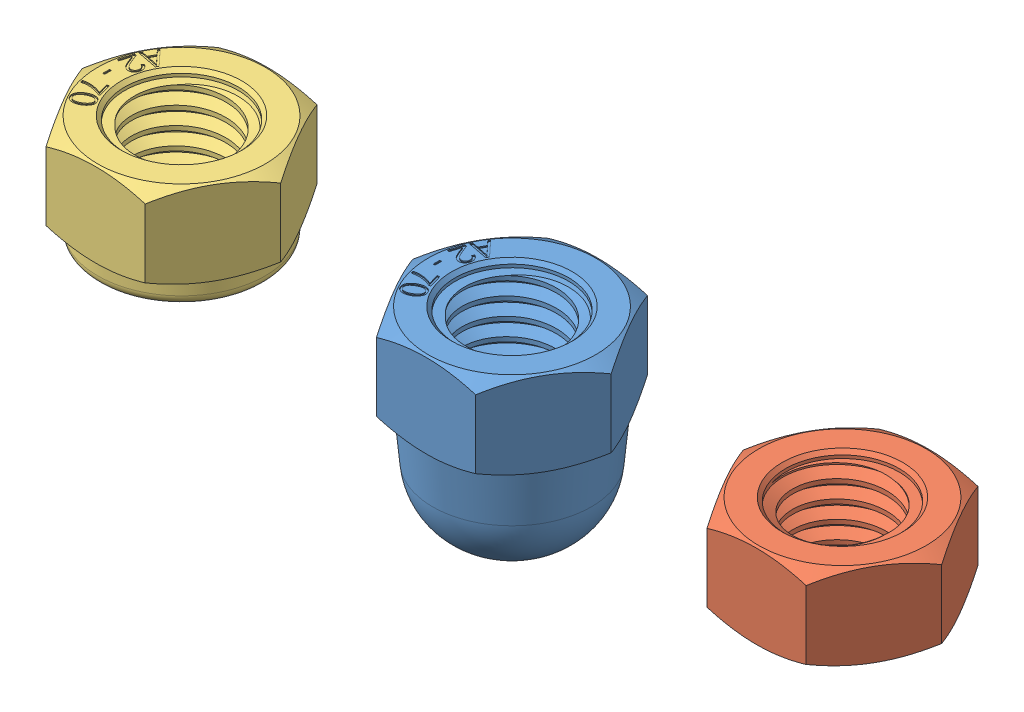
SolidWorks assembly M5 Nuts, configuration Default. Lengths in mm.
Overall size (39.01 9.35 7.8).
3 component instances, 3 part files, 6 mates.
Components (placement in the parent):
- M5 Dome nut-1: M5 Dome nut [Default] at (-16.4148 13.5987 11.7536) size (9.01 9.35 7.8)
- M5 Hex nut-1: M5 Hex nut [Default] at (-1.4148 13.5987 11.7536) x (-1 0 0) z (0 0 1) size (9.01 4.6 7.8)
- M5 Lock nut-1: M5 Lock nut [Default] at (-31.4148 13.5987 11.7536) size (9.01 5.2 7.8)
Mates (geometry in assembly coordinates):
- Coincident1: coincident aligned: plane of M5 Dome nut-1 through (-16.4148 13.5987 11.7536) normal (0 0 1); plane of M5 Hex nut-1 through (-1.4148 13.5987 11.7536) normal (0 0 1)
- Distance1: distance = 15 mm anti-aligned: plane of M5 Dome nut-1 through (-16.4148 13.5987 11.7536) normal (1 0 0); plane of M5 Hex nut-1 through (-1.4148 13.5987 11.7536) normal (-1 0 0)
- Coincident3: coincident anti-aligned: plane of M5 Dome nut-1 through (-16.4148 13.5987 11.7536) normal (0 1 0); plane of M5 Hex nut-1 through (-1.4148 13.5987 11.7536) normal (0 -1 0)
- Distance2: distance = 15 mm: plane of M5 Lock nut-1 through (-31.4148 13.5987 11.7536) normal (1 0 0); plane of M5 Dome nut-1 through (-16.4148 13.5987 11.7536) normal (1 0 0)
- Coincident5: coincident: plane of M5 Dome nut-1 through (-16.4148 13.5987 11.7536) normal (0 1 0); plane of M5 Lock nut-1 through (-31.4148 13.5987 11.7536) normal (0 1 0)
- Coincident6: coincident aligned: plane of M5 Dome nut-1 through (-16.4148 13.5987 11.7536) normal (0 0 1); plane of M5 Lock nut-1 through (-31.4148 13.5987 11.7536) normal (0 0 1)
